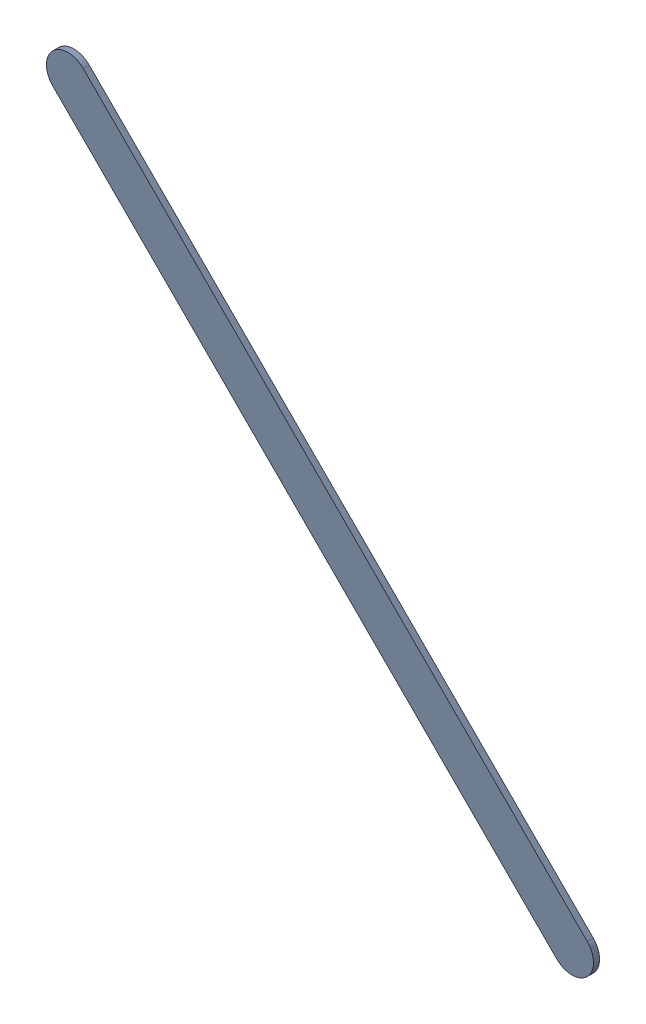
SolidWorks assembly Track (10.2mm,37.8mm)(13.178mm,34.822mm) on Top Layer, configuration Predeterminado. Lengths in mm.
Overall size (3.23 3.23 0.04).
2 component instances, 1 part files, 0 mates.
Components (placement in the parent):
- Track (10.2mm,37.8mm)(13.178mm,34.822mm) on Top Layer-1-1: Track (10.2mm,37.8mm)(13.178mm,34.822mm) on Top Layer-1 [Predeterminado] at (-68.317 -44.187 -0.0457) size (3.23 3.23 0.04)
  - Track (10.2mm,37.8mm)(13.178mm,34.822mm) on Top Layer-Part-1-1: Track (10.2mm,37.8mm)(13.178mm,34.822mm) on Top Layer-Part-1 [Predeterminado] at origin size (3.23 3.23 0.04)
